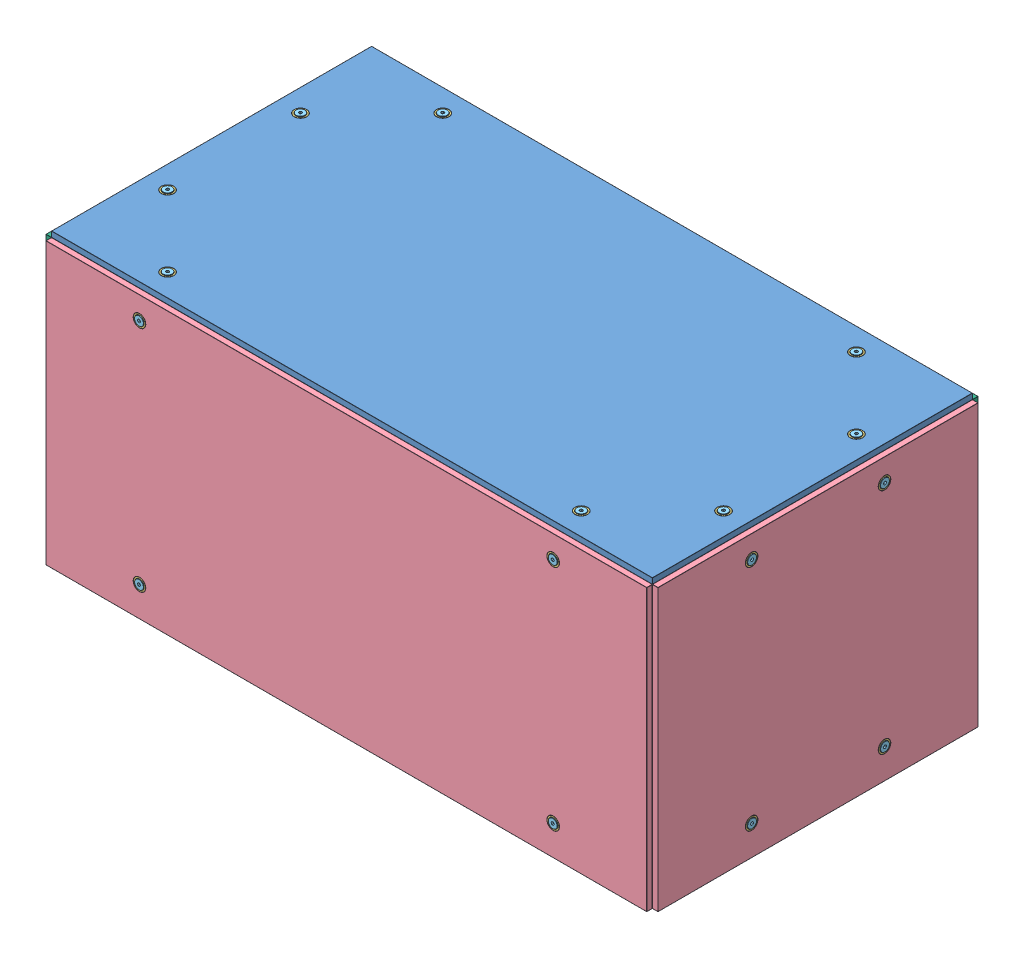
SolidWorks assembly SC.1.GD-VC, configuration Glass Dome 654 x 354 x 300. Lengths in mm.
Overall size (655.03 306.51 355.03).
85 component instances, 7 part files, 48 mates.
Components (placement in the parent):
- SC.1.G.VC.T-1: SC.1.G.VC.T [Topo 642 x 342] at (-2.0067 135.176 -92.8158) size (642 6 342)
- SC.1.L-1: SC.1.L [Default] at (-229.5067 117.926 60.9342) x (0 0 -1) z (1 0 0)
- SC.1.AC2-1: SC.1.AC2 [Default] at (-223.0067 136.176 54.1842) x (0 -1 0) z (0 0 1)
- SC.1.L-2: SC.1.L [Default] at (301.7433 117.926 -15.3158) x (-1 0 0) z (0 0 -1)
- SC.1.AC2-2: SC.1.AC2 [Default] at (294.9933 136.176 -21.8158) x (0 -1 0) z (0 0 1)
- SC.1.AC2-3: SC.1.AC2 [Default] at (218.9933 136.176 54.1842) x (0 -1 0) z (0 0 -1)
- SC.1.L-3: SC.1.L [Default] at (212.4933 117.926 60.9342) x (0 0 -1) z (1 0 0)
- SC.1.AC2-4: SC.1.AC2 [Default] at (294.9933 136.176 -163.8158) x (0 -1 0) z (0 0 1)
- SC.1.L-4: SC.1.L [Default] at (301.7433 117.926 -157.3158) x (-1 0 0) z (0 0 -1)
- SC.1.AC2-5: SC.1.AC2 [Default] at (-299.0067 136.176 -21.8158) x (0 -1 0) z (0 0 -1)
- SC.1.L-5: SC.1.L [Default] at (-305.7567 117.926 -28.3158)
- SC.1.AC2-6: SC.1.AC2 [Default] at (-299.0067 136.176 -163.8158) x (0 -1 0) z (0 0 -1)
- SC.1.L-6: SC.1.L [Default] at (-305.7567 117.926 -170.3158)
- SC.1.AC2-7: SC.1.AC2 [Default] at (218.9933 136.176 -239.8158) x (0 -1 0) z (0 0 -1)
- SC.1.L-7: SC.1.L [Default] at (225.4933 117.926 -246.5658) x (0 0 1) z (-1 0 0)
- SC.1.AC2-8: SC.1.AC2 [Default] at (-223.0067 136.176 -239.8158) x (0 -1 0) z (0 0 1)
- SC.1.L-8: SC.1.L [Default] at (-216.5067 117.926 -246.5658) x (0 0 1) z (-1 0 0)
- SC.1.G.VC.L-1: SC.1.G.VC.L [Lateral 642 x 300] at (-2.0067 -14.824 78.1842)
- SC.1.G.VC.L-5: SC.1.G.VC.L [Lateral 342 x 300] at (318.9933 -14.824 -92.8158) x (0 0 -1) z (1 0 0)
- SC.1.AC2-10: SC.1.AC2 [Default] at (-223.0067 111.176 79.1842) x (0 0 -1) z (0.953116 -0.302606 0)
- SC.1.AC2-11: SC.1.AC2 [Default] at (319.9933 111.176 -21.8158) x (-1 0 0) z (0 0.226252 0.974069)
- SC.1.P7991-12-1: SC.1.P7991-12 [ISO 10642 - M5 x 12 --- 12N] at (-223.0067 141.6902 54.1842) x (0 -1 0) z (0 0 1)
- SC.1.P7991-12-17: SC.1.P7991-12 [ISO 10642 - M5 x 12 --- 12N] at (-223.0067 111.176 84.6984) x (0 0 -1) z (0 -1 0)
- SC.1.P7991-12-21: SC.1.P7991-12 [ISO 10642 - M5 x 12 --- 12N] at (294.9933 141.6902 -21.8158) x (0 -1 0) z (0 0 1)
- SC.1.P7991-12-25: SC.1.P7991-12 [ISO 10642 - M5 x 12 --- 12N] at (325.5075 111.176 -21.8158) x (-1 0 0) z (0 0.987989 0.154525)
- SC.1.P7991-12-5: SC.1.P7991-12 [ISO 10642 - M5 x 12 --- 12N] at (218.9933 141.6902 54.1842) x (0 -1 0) z (0 0 -1)
- SC.1.P7991-12-18: SC.1.P7991-12 [ISO 10642 - M5 x 12 --- 12N] at (218.9933 111.176 84.6984) x (0 0 -1) z (0 1 0)
- SC.1.AC2-12: SC.1.AC2 [Default] at (218.9933 111.176 79.1842) x (0 0 -1) z (0.953116 0.302606 0)
- SC.1.P7991-12-22: SC.1.P7991-12 [ISO 10642 - M5 x 12 --- 12N] at (294.9933 141.6902 -163.8158) x (0 -1 0) z (0 0 1)
- SC.1.P7991-12-26: SC.1.P7991-12 [ISO 10642 - M5 x 12 --- 12N] at (325.5075 111.176 -163.8158) x (-1 0 0) z (0 -0.987989 0.154525)
- SC.1.AC2-13: SC.1.AC2 [Default] at (319.9933 111.176 -163.8158) x (-1 0 0) z (0 -0.226252 0.974069)
- SC.1.P7991-12-24: SC.1.P7991-12 [ISO 10642 - M5 x 12 --- 12N] at (-299.0067 141.6902 -21.8158) x (0 -1 0) z (0 0 -1)
- SC.1.AC2-14: SC.1.AC2 [Default] at (-324.0067 111.176 -21.8158) x (1 0 0) z (0 -0.226252 -0.974069)
- SC.1.P7991-12-28: SC.1.P7991-12 [ISO 10642 - M5 x 12 --- 12N] at (-329.5209 111.176 -21.8158) x (1 0 0) z (0 -0.987989 -0.154525)
- MirrorSC.1.G.VC.L-6: MirrorSC.1.G.VC.L [Lateral 342 x 300] at (-323.0067 -14.824 -92.8158) x (0 0 -1) z (1 0 0)
- SC.1.P7991-12-27: SC.1.P7991-12 [ISO 10642 - M5 x 12 --- 12N] at (-329.5209 111.176 -163.8158) x (1 0 0) z (0 0.987989 -0.154525)
- SC.1.AC2-15: SC.1.AC2 [Default] at (-324.0067 111.176 -163.8158) x (1 0 0) z (0 0.226252 -0.974069)
- SC.1.P7991-12-23: SC.1.P7991-12 [ISO 10642 - M5 x 12 --- 12N] at (-299.0067 141.6902 -163.8158) x (0 -1 0) z (0 0 -1)
- SC.1.P7991-12-20: SC.1.P7991-12 [ISO 10642 - M5 x 12 --- 12N] at (-223.0067 111.176 -270.33) x (0 0 1) z (0 1 0)
- SC.1.AC2-16: SC.1.AC2 [Default] at (-223.0067 111.176 -264.8158) x (0 0 1) z (-0.953116 0.302606 0)
- SC.1.P7991-12-16: SC.1.P7991-12 [ISO 10642 - M5 x 12 --- 12N] at (-223.0067 141.6902 -239.8158) x (0 -1 0) z (0 0 1)
- SC.1.P7991-12-15: SC.1.P7991-12 [ISO 10642 - M5 x 12 --- 12N] at (218.9933 141.6902 -239.8158) x (0 -1 0) z (0 0 -1)
- SC.1.P7991-12-19: SC.1.P7991-12 [ISO 10642 - M5 x 12 --- 12N] at (218.9933 111.176 -270.33) x (0 0 1) z (0 -1 0)
- SC.1.AC2-17: SC.1.AC2 [Default] at (218.9933 111.176 -264.8158) x (0 0 1) z (-0.953116 -0.302606 0)
- MirrorSC.1.G.VC.L-7: MirrorSC.1.G.VC.L [Lateral 642 x 300] at (-2.0067 -14.824 -263.8158)
- SC.1.P7991-12-29: SC.1.P7991-12 [ISO 10642 - M5 x 12 --- 12N] at (-223.0067 -132.824 84.6984) x (0 0 -1) z (0 -1 0)
- SC.1.AC2-18: SC.1.AC2 [Default] at (-223.0067 -132.824 79.1842) x (0 0 -1) z (0.803409 0.595428 0)
- SC.1.P7991-12-33: SC.1.P7991-12 [ISO 10642 - M5 x 12 --- 12N] at (325.5075 -132.824 -21.8158) x (-1 0 0) z (0 -0.850148 0.526544)
- SC.1.AC2-19: SC.1.AC2 [Default] at (319.9933 -132.824 -21.8158) x (-1 0 0) z (0 0 1)
- SC.1.P7991-12-30: SC.1.P7991-12 [ISO 10642 - M5 x 12 --- 12N] at (218.9933 -132.824 84.6984) x (0 0 -1) z (0 1 0)
- SC.1.AC2-20: SC.1.AC2 [Default] at (218.9933 -132.824 79.1842) x (0 0 -1) z (0.803409 -0.595428 0)
- SC.1.P7991-12-34: SC.1.P7991-12 [ISO 10642 - M5 x 12 --- 12N] at (325.5075 -132.824 -163.8158) x (-1 0 0) z (0 0.850148 0.526544)
- SC.1.AC2-21: SC.1.AC2 [Default] at (319.9933 -132.824 -163.8158) x (-1 0 0) z (0 0 1)
- SC.1.P7991-12-36: SC.1.P7991-12 [ISO 10642 - M5 x 12 --- 12N] at (-329.5209 -132.824 -21.8158) x (1 0 0) z (0 0.850148 -0.526544)
- SC.1.AC2-22: SC.1.AC2 [Default] at (-324.0067 -132.824 -21.8158) x (1 0 0) z (0 0 -1)
- SC.1.P7991-12-35: SC.1.P7991-12 [ISO 10642 - M5 x 12 --- 12N] at (-329.5209 -132.824 -163.8158) x (1 0 0) z (0 -0.850148 -0.526544)
- SC.1.AC2-23: SC.1.AC2 [Default] at (-324.0067 -132.824 -163.8158) x (1 0 0) z (0 0 -1)
- SC.1.AC2-24: SC.1.AC2 [Default] at (-223.0067 -132.824 -264.8158) x (0 0 1) z (-0.803409 -0.595428 0)
- SC.1.P7991-12-32: SC.1.P7991-12 [ISO 10642 - M5 x 12 --- 12N] at (-223.0067 -132.824 -270.33) x (0 0 1) z (0 1 0)
- SC.1.AC2-25: SC.1.AC2 [Default] at (218.9933 -132.824 -264.8158) x (0 0 1) z (-0.803409 0.595428 0)
- SC.1.P7991-12-31: SC.1.P7991-12 [ISO 10642 - M5 x 12 --- 12N] at (218.9933 -132.824 -270.33) x (0 0 1) z (0 -1 0)
- SC.1.A-1: SC.1.A [Default] at (-223.0067 131.176 54.1842) x (0 1 0) z (0 0 1) size (4 13 13)
- SC.1.A-4: SC.1.A [Default] at (-223.0067 -132.824 74.1842) x (0 0 1) z (0 -1 0) size (4 13 13)
- SC.1.A-6: SC.1.A [Default] at (294.9933 131.176 -21.8158) x (0 1 0) z (0 0 1) size (4 13 13)
- SC.1.A-7: SC.1.A [Default] at (314.9933 111.176 -21.8158) x (1 0 0) z (0 0.925439 -0.378896) size (4 13 13)
- SC.1.A-8: SC.1.A [Default] at (314.9933 -132.824 -21.8158) size (4 13 13)
- SC.1.A-9: SC.1.A [Default] at (218.9933 131.176 54.1842) x (0 1 0) z (0 0 -1) size (4 13 13)
- SC.1.A-10: SC.1.A [Default] at (218.9933 -132.824 74.1842) x (0 0 1) z (0 1 0) size (4 13 13)
- SC.1.A-11: SC.1.A [Default] at (294.9933 131.176 -163.8158) x (0 1 0) z (0 0 1) size (4 13 13)
- SC.1.A-12: SC.1.A [Default] at (314.9933 111.176 -163.8158) x (1 0 0) z (0 -0.925439 -0.378896) size (4 13 13)
- SC.1.A-13: SC.1.A [Default] at (314.9933 -132.824 -163.8158) size (4 13 13)
- SC.1.A-14: SC.1.A [Default] at (-319.0067 -132.824 -21.8158) x (-1 0 0) z (0 0 -1) size (4 13 13)
- SC.1.A-15: SC.1.A [Default] at (-319.0067 -132.824 -163.8158) x (-1 0 0) z (0 0 -1) size (4 13 13)
- SC.1.A-16: SC.1.A [Default] at (-319.0067 111.176 -21.8158) x (-1 0 0) z (0 -0.925439 0.378896) size (4 13 13)
- SC.1.A-17: SC.1.A [Default] at (-299.0067 131.176 -21.8158) x (0 1 0) z (0 0 -1) size (4 13 13)
- SC.1.A-18: SC.1.A [Default] at (-319.0067 111.176 -163.8158) x (-1 0 0) z (0 0.925439 0.378896) size (4 13 13)
- SC.1.A-19: SC.1.A [Default] at (-299.0067 131.176 -163.8158) x (0 1 0) z (0 0 -1) size (4 13 13)
- SC.1.A-20: SC.1.A [Default] at (-223.0067 -132.824 -259.8158) x (0 0 -1) z (0 1 0) size (4 13 13)
- SC.1.A-21: SC.1.A [Default] at (-223.0067 131.176 -239.8158) x (0 1 0) z (0 0 1) size (4 13 13)
- SC.1.A-22: SC.1.A [Default] at (218.9933 131.176 -239.8158) x (0 1 0) z (0 0 -1) size (4 13 13)
- SC.1.A-23: SC.1.A [Default] at (218.9933 -132.824 -259.8158) x (0 0 -1) z (0 -1 0) size (4 13 13)
- SC.1.A-24: SC.1.A [Default] at (-223.0067 111.176 74.1842) x (0 0 1) z (-0.524225 -0.85158 0) size (4 13 13)
- SC.1.A-25: SC.1.A [Default] at (218.9933 111.176 74.1842) x (0 0 1) z (-0.524225 0.85158 0) size (4 13 13)
- SC.1.A-26: SC.1.A [Default] at (-223.0067 111.176 -259.8158) x (0 0 -1) z (0.524225 0.85158 0) size (4 13 13)
- SC.1.A-27: SC.1.A [Default] at (218.9933 111.176 -259.8158) x (0 0 -1) z (0.524225 -0.85158 0) size (4 13 13)
Mates (geometry in assembly coordinates):
- Concentric3: concentric aligned: cylinder of SC.1.G.VC.T-1 through (-223.0067 135.176 54.1842) axis (0 1 0) radius 4; cylinder of SC.1.AC2-1 through (-223.0067 145.7556 54.1842) axis (0 1 0) radius 4
- Coincident2: coincident aligned: plane of SC.1.AC2-1 through (-216.5067 141.176 54.1842) normal (0 1 0); plane of SC.1.G.VC.T-1 through (-2.0067 141.176 -92.8158) normal (0 1 0)
- Concentric7: concentric aligned: cylinder of SC.1.L-1 through (-223.0067 131.176 54.1842) axis (0 1 0) radius 2.1; cylinder of SC.1.AC2-1 through (-223.0067 145.7556 54.1842) axis (0 1 0) radius 4
- Parallel1: parallel aligned: plane of SC.1.G.VC.T-1 through (-323.0067 141.176 78.1842) normal (0 0 1); plane of SC.1.L-1 through (-216.5067 131.176 74.1842) normal (0 0 1)
- Concentric10: concentric aligned: cylinder of SC.1.L-2 through (294.9933 131.176 -21.8158) axis (0 1 0) radius 2.1; cylinder of SC.1.AC2-2 through (294.9933 145.7556 -21.8158) axis (0 1 0) radius 4
- Concentric11: concentric aligned: cylinder of SC.1.G.VC.T-1 through (294.9933 135.176 -21.8158) axis (0 1 0) radius 4; cylinder of SC.1.AC2-2 through (294.9933 145.7556 -21.8158) axis (0 1 0) radius 4
- Coincident9: coincident aligned: plane of SC.1.AC2-2 through (301.4933 141.176 -21.8158) normal (0 1 0); plane of SC.1.G.VC.T-1 through (-2.0067 141.176 -92.8158) normal (0 1 0)
- Parallel2: parallel aligned: plane of SC.1.G.VC.T-1 through (318.9933 141.176 -263.8158) normal (1 0 0); plane of SC.1.L-2 through (314.9933 131.176 -28.3158) normal (1 0 0)
- Concentric16: concentric aligned: cylinder of SC.1.L-1 through (-223.0067 111.176 74.1842) axis (0 0 1) radius 2.1; cylinder of SC.1.G.VC.L-1 through (-223.0067 111.176 78.1842) axis (0 0 1) radius 4
- Concentric17: concentric aligned: cylinder of SC.1.L-3 through (218.9933 111.176 74.1842) axis (0 0 1) radius 2.1; cylinder of SC.1.G.VC.L-1 through (218.9933 111.176 78.1842) axis (0 0 1) radius 4
- Concentric20: concentric aligned: cylinder of SC.1.L-2 through (314.9933 111.176 -21.8158) axis (1 0 0) radius 2.1; cylinder of SC.1.G.VC.L-5 through (318.9933 111.176 -21.8158) axis (1 0 0) radius 4
- Concentric21: concentric aligned: cylinder of SC.1.L-4 through (314.9933 111.176 -163.8158) axis (1 0 0) radius 2.1; cylinder of SC.1.G.VC.L-5 through (318.9933 111.176 -163.8158) axis (1 0 0) radius 4
- Concentric22: concentric aligned: cylinder of SC.1.G.VC.L-1 through (-223.0067 111.176 78.1842) axis (0 0 1) radius 4; cylinder of SC.1.AC2-10 through (-223.0067 111.176 88.7638) axis (0 0 1) radius 4
- Coincident21: coincident aligned: plane of SC.1.AC2-10 through (-221.0398 117.3712 84.1842) normal (0 0 1); plane of SC.1.G.VC.L-1 through (-2.0067 -14.824 84.1842) normal (0 0 1)
- Concentric23: concentric aligned: cylinder of SC.1.G.VC.L-5 through (318.9933 111.176 -21.8158) axis (1 0 0) radius 4; cylinder of SC.1.AC2-11 through (329.5729 111.176 -21.8158) axis (1 0 0) radius 4
- Coincident22: coincident aligned: plane of SC.1.AC2-11 through (324.9933 104.8445 -20.3452) normal (1 0 0); plane of SC.1.G.VC.L-5 through (324.9933 -14.824 -92.8158) normal (1 0 0)
- Concentric24: concentric aligned: cylinder of SC.1.P7991-12-1 through (-223.0067 141.6902 54.1842) axis (0 1 0) radius 2.5; cylinder of SC.1.AC2-1 through (-223.0067 145.7556 54.1842) axis (0 1 0) radius 4
- Coincident23: coincident aligned: cone of SC.1.AC2-1 through (-223.0067 141.176 54.1842) axis (0 -1 0); cone of SC.1.P7991-12-1 through (-223.0067 140.8052 54.1842) axis (0 -1 0)
- Concentric26: concentric aligned: cylinder of SC.1.AC2-10 through (-223.0067 111.176 88.7638) axis (0 0 1) radius 4; cylinder of SC.1.P7991-12-17 through (-223.0067 111.176 84.6984) axis (0 0 1) radius 2.5
- Coincident24: coincident aligned: cone of SC.1.AC2-10 through (-223.0067 111.176 84.1842) axis (0 0 -1); cone of SC.1.P7991-12-17 through (-223.0067 111.176 83.8134) axis (0 0 -1)
- Concentric27: concentric aligned: cylinder of SC.1.P7991-12-21 through (294.9933 141.6902 -21.8158) axis (0 1 0) radius 2.5; cylinder of SC.1.AC2-2 through (294.9933 145.7556 -21.8158) axis (0 1 0) radius 4
- Coincident25: coincident aligned: cone of SC.1.AC2-2 through (294.9933 141.176 -21.8158) axis (0 -1 0); cone of SC.1.P7991-12-21 through (294.9933 140.8052 -21.8158) axis (0 -1 0)
- Concentric28: concentric aligned: cylinder of SC.1.AC2-11 through (329.5729 111.176 -21.8158) axis (1 0 0) radius 4; cylinder of SC.1.P7991-12-25 through (325.5075 111.176 -21.8158) axis (1 0 0) radius 2.5
- Coincident26: coincident aligned: cone of SC.1.AC2-11 through (324.9933 111.176 -21.8158) axis (-1 0 0); cone of SC.1.P7991-12-25 through (324.6225 111.176 -21.8158) axis (-1 0 0)
- Concentric31: concentric aligned: cylinder of SC.1.P7991-12-29 through (-223.0067 -132.824 84.6984) axis (0 0 1) radius 2.5; cylinder of SC.1.AC2-18 through (-223.0067 -132.824 88.7638) axis (0 0 1) radius 4
- Coincident28: coincident aligned: cone of SC.1.P7991-12-29 through (-223.0067 -132.824 83.8134) axis (0 0 -1); cone of SC.1.AC2-18 through (-223.0067 -132.824 84.1842) axis (0 0 -1)
- Concentric32: concentric aligned: cylinder of SC.1.G.VC.L-1 through (-223.0067 -132.824 78.1842) axis (0 0 1) radius 4; cylinder of SC.1.AC2-18 through (-223.0067 -132.824 88.7638) axis (0 0 1) radius 4
- Coincident29: coincident aligned: plane of SC.1.AC2-18 through (-226.877 -127.6019 84.1842) normal (0 0 1); plane of SC.1.G.VC.L-1 through (-2.0067 -14.824 84.1842) normal (0 0 1)
- Concentric35: concentric aligned: cylinder of SC.1.P7991-12-33 through (325.5075 -132.824 -21.8158) axis (1 0 0) radius 2.5; cylinder of SC.1.AC2-19 through (329.5729 -132.824 -21.8158) axis (1 0 0) radius 4
- Coincident32: coincident aligned: cone of SC.1.P7991-12-33 through (324.6225 -132.824 -21.8158) axis (-1 0 0); cone of SC.1.AC2-19 through (324.9933 -132.824 -21.8158) axis (-1 0 0)
- Concentric36: concentric aligned: cylinder of SC.1.G.VC.L-5 through (318.9933 -132.824 -21.8158) axis (1 0 0) radius 4; cylinder of SC.1.AC2-19 through (329.5729 -132.824 -21.8158) axis (1 0 0) radius 4
- Coincident33: coincident aligned: plane of SC.1.G.VC.L-5 through (324.9933 -14.824 -92.8158) normal (1 0 0); plane of SC.1.AC2-19 through (324.9933 -139.324 -21.8158) normal (1 0 0)
- Concentric37: concentric anti-aligned: cylinder of SC.1.AC2-1 through (-223.0067 145.7556 54.1842) axis (0 1 0) radius 4; cylinder of SC.1.A-1 through (-223.0067 135.176 54.1842) axis (0 -1 0) radius 4
- Coincident35: coincident anti-aligned: plane of SC.1.G.VC.T-1 through (-2.0067 135.176 -92.8158) normal (0 -1 0); plane of SC.1.A-1 through (-223.0067 135.176 54.1842) normal (0 1 0)
- Concentric38: concentric anti-aligned: cylinder of SC.1.AC2-18 through (-223.0067 -132.824 88.7638) axis (0 0 1) radius 4; cylinder of SC.1.A-4 through (-223.0067 -132.824 78.1842) axis (0 0 -1) radius 4
- Coincident36: coincident anti-aligned: plane of SC.1.G.VC.L-1 through (-2.0067 -14.824 78.1842) normal (0 0 -1); plane of SC.1.A-4 through (-223.0067 -132.824 78.1842) normal (0 0 1)
- Concentric40: concentric anti-aligned: cylinder of SC.1.AC2-2 through (294.9933 145.7556 -21.8158) axis (0 1 0) radius 4; cylinder of SC.1.A-6 through (294.9933 135.176 -21.8158) axis (0 -1 0) radius 4
- Coincident38: coincident anti-aligned: plane of SC.1.G.VC.T-1 through (-2.0067 135.176 -92.8158) normal (0 -1 0); plane of SC.1.A-6 through (294.9933 135.176 -21.8158) normal (0 1 0)
- Concentric41: concentric anti-aligned: cylinder of SC.1.AC2-11 through (329.5729 111.176 -21.8158) axis (1 0 0) radius 4; cylinder of SC.1.A-7 through (318.9933 111.176 -21.8158) axis (-1 0 0) radius 4
- Coincident39: coincident anti-aligned: plane of SC.1.G.VC.L-5 through (318.9933 -14.824 -92.8158) normal (-1 0 0); plane of SC.1.A-7 through (318.9933 111.176 -21.8158) normal (1 0 0)
- Concentric42: concentric anti-aligned: cylinder of SC.1.AC2-19 through (329.5729 -132.824 -21.8158) axis (1 0 0) radius 4; cylinder of SC.1.A-8 through (318.9933 -132.824 -21.8158) axis (-1 0 0) radius 4
- Coincident40: coincident anti-aligned: plane of SC.1.G.VC.L-5 through (318.9933 -14.824 -92.8158) normal (-1 0 0); plane of SC.1.A-8 through (318.9933 -132.824 -21.8158) normal (1 0 0)
- Concentric43: concentric anti-aligned: cylinder of SC.1.AC2-10 through (-223.0067 111.176 88.7638) axis (0 0 1) radius 4; cylinder of SC.1.A-24 through (-223.0067 111.176 78.1842) axis (0 0 -1) radius 4
- Coincident41: coincident anti-aligned: plane of SC.1.G.VC.L-1 through (-2.0067 -14.824 78.1842) normal (0 0 -1); plane of SC.1.A-24 through (-223.0067 111.176 78.1842) normal (0 0 1)
- Coincident43: coincident anti-aligned: plane of SC.1.L-1 through (-216.5067 131.176 47.6842) normal (0 1 0); plane of SC.1.A-1 through (-223.0067 131.176 54.1842) normal (0 -1 0)
- Coincident44: coincident anti-aligned: plane of SC.1.L-1 through (-216.5067 131.176 74.1842) normal (0 0 1); plane of SC.1.A-24 through (-223.0067 111.176 74.1842) normal (0 0 -1)
- Coincident45: coincident anti-aligned: plane of SC.1.L-5 through (-292.5067 131.176 -15.3158) normal (0 1 0); plane of SC.1.A-17 through (-299.0067 131.176 -21.8158) normal (0 -1 0)
- Coincident46: coincident anti-aligned: plane of SC.1.L-5 through (-319.0067 131.176 -15.3158) normal (-1 0 0); plane of SC.1.A-16 through (-319.0067 111.176 -21.8158) normal (1 0 0)
